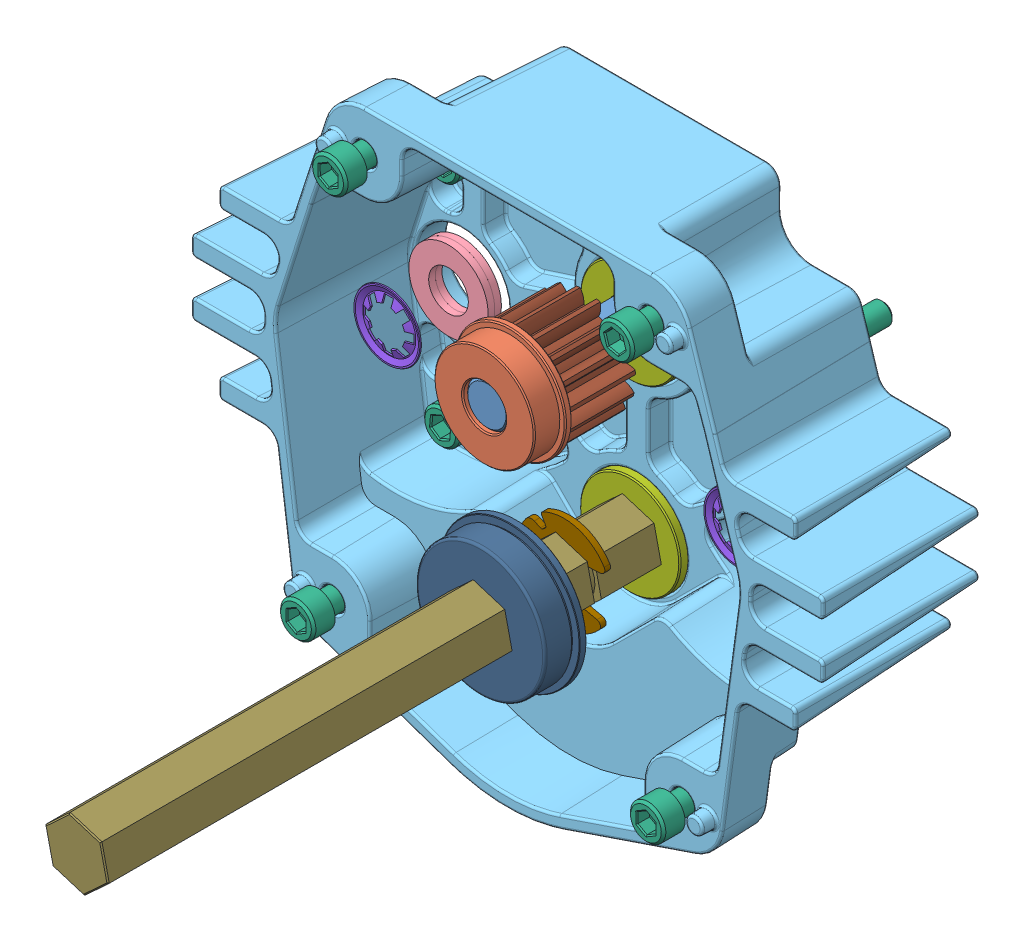
SolidWorks assembly ToughboxMini, configuration Default. Lengths in mm.
Overall size (140.05 118.73 142.29).
27 component instances, 15 part files, 55 mates.
Components (placement in the parent):
- TBMiniSmallHexShaft-1: TBMiniSmallHexShaft [Default] at (-129.7894 33.1737 -52.3959) x (-0.674239 -0.738513 0) z (-0.738513 0.674239 0) size (11 38.23 9.52)
- Bearing_FR6ZZ-1: Bearing_FR6ZZ [Default] at (-96.247 60.278 -52.5991) x (-0.893862 0.448342 0) z (0 0 1) size (24.69 24.69 7.16)
- NylockNut_10-32-1: NylockNut_10-32 [Default] at (-129.8464 -8.0737 -56.3837) x (0.501678 0.865055 0) z (0 0 -1) size (10.18 11.01 7.1)
- NylockNut_10-32-2: NylockNut_10-32 [Default] at (-59.2462 80.7349 -56.3837) x (0.999999 -0.001296 0) z (0 0 -1) size (10.18 11.01 7.1)
- NylockNut_10-32-3: NylockNut_10-32 [Default] at (-122.7461 80.8172 -56.3837) x (0.500567 0.865698 0) z (0 0 -1) size (10.18 11.01 7.1)
- NylockNut_10-32-4: NylockNut_10-32 [Default] at (-52.3764 -8.1741 -56.3837) x (-0.501678 -0.865055 0) z (0 0 -1) size (10.18 11.01 7.1)
- Washer_5-16-1: Washer_5-16 [Default] at (-52.3162 38.3079 -77.7705) x (-0.418041 0.908428 0) z (0 0 -1) size (17.53 17.53 1.47)
- Washer_5-16-2: Washer_5-16 [Default] at (-52.3162 38.3079 -76.2973) x (0.897267 -0.441488 0) z (0 0 -1) size (17.53 17.53 1.47)
- Washer_5-16-3: Washer_5-16 [Default] at (-129.7861 38.4083 -77.7705) x (-0.990116 0.140253 0) z (0 0 1) size (17.53 17.53 1.47)
- Washer_5-16-4: Washer_5-16 [Default] at (-129.7861 38.4083 -79.2437) x (-0.681761 0.731575 0) z (0 0 1) size (17.53 17.53 1.47)
- TBMiniHousing-1: TBMiniHousing [Default] at (-91.0876 10.1882 -86.3557) x (0.999999 -0.001296 0) z (0 0 1) size (139.9 118.55 41.54)
- Screw_SHCS_10-32x0.625-1: Screw_SHCS_10-32x0.625 [Default] at (-52.2832 63.7078 -74.4685) x (-0.564778 -0.825243 0) z (-0.825243 0.564778 0) size (7.82 20.65 7.82)
- Screw_SHCS_10-32x0.625-2: Screw_SHCS_10-32x0.625 [Default] at (-122.7461 80.8172 -42.5915) x (0.507484 -0.861661 0) z (-0.861661 -0.507484 0) size (7.82 20.65 7.82)
- Screw_SHCS_10-32x0.625-3: Screw_SHCS_10-32x0.625 [Default] at (-52.3764 -8.1741 -42.5915) x (0.507484 -0.861661 0) z (-0.861661 -0.507484 0) size (7.82 20.65 7.82)
- Screw_SHCS_10-32x0.625-4: Screw_SHCS_10-32x0.625 [Default] at (-129.8464 -8.0737 -42.5915) x (0.507484 -0.861661 0) z (-0.861661 -0.507484 0) size (7.82 20.65 7.82)
- Screw_SHCS_10-32x0.625-5: Screw_SHCS_10-32x0.625 [Default] at (-59.2462 80.7349 -42.5915) x (0.740711 -0.671824 0) z (-0.671824 -0.740711 0) size (7.82 20.65 7.82)
- Screw_SHCS_10-32x0.625-6: Screw_SHCS_10-32x0.625 [Default] at (-52.3491 12.9079 -74.4685) x (-0.564778 -0.825243 0) z (-0.825243 0.564778 0) size (7.82 20.65 7.82)
- Screw_SHCS_10-32x0.625-7: Screw_SHCS_10-32x0.625 [Default] at (-129.7532 63.8083 -74.4685) x (-0.966277 -0.257503 0) z (-0.257503 0.966277 0) size (7.82 20.65 7.82)
- Screw_SHCS_10-32x0.625-8: Screw_SHCS_10-32x0.625 [Default] at (-129.819 13.0083 -74.4685) x (-0.99652 0.083357 0) z (0.083357 0.99652 0) size (7.82 20.65 7.82)
- Bearing_R6ZZ-3: Bearing_R6ZZ [Default] at (-91.0349 50.9043 -84.8317) x (0.958138 -0.286306 0) z (0 0 1) size (22.23 22.23 7.11)
- Bearing_R6ZZ-4: Bearing_R6ZZ [Default] at (-91.0876 10.1882 -84.8317) x (-0.661529 0.74992 0) z (0 0 1) size (22.23 22.23 7.11)
- RetainingClip-1: RetainingClip [Default] at (-129.7861 38.4083 -63.5973) x (0 0 1) z (-1 0 0) size (1.09 14.83 14.83)
- RetainingClip-2: RetainingClip [Default] at (-52.3162 38.3079 -63.5973) x (0 0 1) z (-1 0 0) size (1.09 14.83 14.83)
- ExternalKlipring-1: ExternalKlipring [Default] at (-91.0876 10.1882 -64.4355) x (0.996411 -0.084651 0) z (0 0 1) size (19.07 20.96 1.27)
- HexBearing_FR8ZZ-1: HexBearing_FR8ZZ [Default] at (-91.0876 10.1882 -44.6717) x (0.73373 0.679441 0) z (0 0 -1) size (31.12 31.12 7.93)
- SmallClusterGear_Hex_16t0.375-1: SmallClusterGear_Hex_16t0.375 [Default] at (-91.0349 50.9043 -67.5597) x (0 0 1) z (0.302452 -0.953165 0) size (15.19 22.57 22.57)
- TBMiniHexOutputShaft-2: TBMiniHexOutputShaft [Default] at (-51.6549 23.9851 -52.3197) x (0.73373 0.679441 0) z (0.679441 -0.73373 0) size (14.66 142.29 12.7)
Mates (geometry in assembly coordinates):
- Concentric2: concentric aligned: circle of NylockNut_10-32-3; circle of TBMiniHousing-1
- Coincident1: coincident anti-aligned: plane of NylockNut_10-32-3 through (-122.7461 80.8172 -56.3837) normal (0 0 1); plane of TBMiniHousing-1 through (-132.6301 80.83 -56.3837) normal (0 0 -1)
- Parallel1: parallel: plane of NylockNut_10-32-3 through (-125.1247 84.9432 -58.368) normal (-0.499433 0.866352 0); line of TBMiniHousing-1 through (-122.993 86.3757 -60.7105) axis (-0.866352 -0.499433 0)
- Concentric3: concentric anti-aligned: circle of NylockNut_10-32-2; circle of TBMiniHousing-1
- Coincident3: coincident anti-aligned: plane of NylockNut_10-32-2 through (-59.2462 80.7349 -56.3837) normal (0 0 1); plane of TBMiniHousing-1 through (-59.2388 86.4499 -56.3837) normal (0 0 -1)
- Parallel2: parallel: plane of NylockNut_10-32-2 through (-54.4837 80.7287 -58.368) normal (0.999999 -0.001296 0); line of TBMiniHousing-1 through (-54.0512 78.1748 -60.9557) axis (0.001296 0.999999 0)
- Concentric4: concentric anti-aligned: circle of NylockNut_10-32-4; circle of TBMiniHousing-1
- Coincident5: coincident anti-aligned: plane of NylockNut_10-32-4 through (-52.3764 -8.1741 -56.3837) normal (0 0 1); plane of TBMiniHousing-1 through (-62.2604 -8.1613 -56.3837) normal (0 0 -1)
- Parallel3: parallel: plane of NylockNut_10-32-4 through (-49.9872 -4.0543 -58.368) normal (0.501678 0.865055 0); line of TBMiniHousing-1 through (-47.5543 -4.9678 -60.9557) axis (-0.865055 0.501678 0)
- Concentric5: concentric aligned: circle of NylockNut_10-32-1; circle of TBMiniHousing-1
- Coincident9: coincident anti-aligned: plane of NylockNut_10-32-1 through (-129.8464 -8.0737 -56.3837) normal (0 0 1); plane of TBMiniHousing-1 through (-139.7304 -8.0609 -56.3837) normal (0 0 -1)
- Parallel4: parallel: plane of NylockNut_10-32-1 through (-132.2356 -12.1935 -58.368) normal (-0.501678 -0.865055 0); line of TBMiniHousing-1 through (-130.235 -13.8511 -60.9557) axis (-0.865055 0.501678 0)
- Concentric6: concentric aligned: cylinder of TBMiniHousing-1 through (-129.7532 63.8083 -50.5417) axis (0 0 1) radius 2.5527; circle of Screw_SHCS_10-32x0.625-7
- Coincident11: coincident anti-aligned: plane of TBMiniHousing-1 through (-59.2462 80.7349 -79.2437) normal (0 0 1); plane of Screw_SHCS_10-32x0.625-7 through (-129.7532 63.8083 -79.2437) normal (0 0 -1)
- Concentric7: concentric anti-aligned: cylinder of TBMiniHousing-1 through (-52.2832 63.7078 -50.5417) axis (0 0 1) radius 2.5527; circle of Screw_SHCS_10-32x0.625-1
- Coincident12: coincident anti-aligned: plane of TBMiniHousing-1 through (-59.2462 80.7349 -79.2437) normal (0 0 1); plane of Screw_SHCS_10-32x0.625-1 through (-52.2832 63.7078 -79.2437) normal (0 0 -1)
- Concentric8: concentric aligned: cylinder of TBMiniHousing-1 through (-52.3491 12.9079 -50.5417) axis (0 0 1) radius 2.5527; cylinder of Screw_SHCS_10-32x0.625-6 through (-52.3491 12.9079 -95.1187) axis (0 0 1) radius 2.3876
- Coincident13: coincident anti-aligned: plane of TBMiniHousing-1 through (-59.2462 80.7349 -79.2437) normal (0 0 1); plane of Screw_SHCS_10-32x0.625-6 through (-52.3491 12.9079 -79.2437) normal (0 0 -1)
- Concentric9: concentric aligned: cylinder of TBMiniHousing-1 through (-129.819 13.0083 -50.5417) axis (0 0 1) radius 2.5527; cylinder of Screw_SHCS_10-32x0.625-8 through (-129.819 13.0083 -95.1187) axis (0 0 1) radius 2.3876
- Coincident14: coincident anti-aligned: plane of TBMiniHousing-1 through (-59.2462 80.7349 -79.2437) normal (0 0 1); plane of Screw_SHCS_10-32x0.625-8 through (-129.819 13.0083 -79.2437) normal (0 0 -1)
- Concentric12: concentric aligned: cylinder of Washer_5-16-3 through (-129.7861 38.4083 -76.2973) axis (0 0 -1) radius 8.763; cylinder of Washer_5-16-4 through (-129.7861 38.4083 -77.7705) axis (0 0 -1) radius 8.763
- Concentric13: concentric anti-aligned: circle of Washer_5-16-4; cylinder of TBMiniHousing-1 through (-129.7861 38.4083 -50.5417) axis (0 0 1) radius 10.414
- Coincident17: coincident anti-aligned: plane of Washer_5-16-4 through (-129.7861 38.4083 -79.2437) normal (0 0 -1); plane of TBMiniHousing-1 through (-59.2462 80.7349 -79.2437) normal (0 0 1)
- Coincident18: coincident anti-aligned: plane of Washer_5-16-3 through (-129.7861 38.4083 -77.7705) normal (0 0 -1); plane of Washer_5-16-4 through (-129.7861 38.4083 -77.7705) normal (0 0 1)
- Coincident21: coincident aligned: circle of Washer_5-16-1; circle of Washer_5-16-2
- Concentric16: concentric aligned: cylinder of Washer_5-16-1 through (-52.3162 38.3079 -79.2437) axis (0 0 1) radius 4.3942; cylinder of TBMiniHousing-1 through (-52.3162 38.3079 -50.5417) axis (0 0 1) radius 10.414
- Coincident22: coincident anti-aligned: plane of Washer_5-16-1 through (-52.3162 38.3079 -79.2437) normal (0 0 -1); plane of TBMiniHousing-1 through (-59.2462 80.7349 -79.2437) normal (0 0 1)
- Concentric27: concentric anti-aligned: cylinder of TBMiniSmallHexShaft-1 through (-91.0349 50.9043 -46.0459) axis (0 0 -1) radius 4.7498; cylinder of Bearing_FR6ZZ-1 through (-91.0349 50.9043 -51.0751) axis (0 0 1) radius 4.7625
- Coincident37: coincident aligned: plane of Screw_SHCS_10-32x0.625-4 through (-129.8464 -8.0737 -47.3667) normal (0 0 -1); plane of Screw_SHCS_10-32x0.625-5 through (-59.2462 80.7349 -47.3667) normal (0 0 -1)
- Coincident39: coincident aligned: plane of Screw_SHCS_10-32x0.625-2 through (-122.7461 80.8172 -47.3667) normal (0 0 -1); plane of Screw_SHCS_10-32x0.625-5 through (-59.2462 80.7349 -47.3667) normal (0 0 -1)
- Coincident40: coincident aligned: plane of Screw_SHCS_10-32x0.625-2 through (-122.7461 80.8172 -47.3667) normal (0 0 -1); plane of Screw_SHCS_10-32x0.625-3 through (-52.3764 -8.1741 -47.3667) normal (0 0 -1)
- Concentric34: concentric anti-aligned: cylinder of TBMiniSmallHexShaft-1 through (-91.0349 50.9043 -84.2729) axis (0 0 1) radius 4.7498; cylinder of Bearing_R6ZZ-3 through (-91.0349 50.9043 -77.7197) axis (0 0 -1) radius 11.1125
- Concentric48: concentric anti-aligned: cylinder of TBMiniHousing-1 through (-91.0876 10.1882 -50.5417) axis (0 0 1) radius 5.08; cylinder of Bearing_R6ZZ-4 through (-91.0876 10.1882 -77.7197) axis (0 0 -1) radius 11.1125
- Coincident60: coincident anti-aligned: plane of TBMiniHousing-1 through (-91.0876 10.1882 -84.8317) normal (0 0 1); plane of Bearing_R6ZZ-4 through (-91.0876 10.1882 -84.8317) normal (0 0 -1)
- Coincident62: coincident aligned: plane of Bearing_FR6ZZ-1 through (-91.0349 50.9043 -51.0751) normal (0 0 1); plane of HexBearing_FR8ZZ-1 through (-80.8374 19.68 -51.0751) normal (0 0 1)
- Coincident63: coincident anti-aligned: plane of TBMiniHousing-1 through (-91.0349 50.9043 -84.8317) normal (0 0 1); plane of Bearing_R6ZZ-3 through (-91.0349 50.9043 -84.8317) normal (0 0 -1)
- Coincident64: coincident anti-aligned: plane of TBMiniSmallHexShaft-1 through (-92.6981 56.146 -77.7197) normal (0 0 -1); plane of Bearing_R6ZZ-3 through (-91.0349 50.9043 -77.7197) normal (0 0 1)
- Coincident69: coincident anti-aligned: plane of TBMiniSmallHexShaft-1 through (-87.327 54.9656 -52.5991) normal (0 0 1); plane of Bearing_FR6ZZ-1 through (-91.0349 50.9043 -52.5991) normal (0 0 -1)
- Concentric52: concentric aligned: cylinder of TBMiniHousing-1 through (-91.0349 50.9043 -84.8317) axis (0 0 -1) radius 11.1061; cylinder of Bearing_R6ZZ-3 through (-91.0349 50.9043 -77.7197) axis (0 0 -1) radius 11.1125
- Distance1: distance = 3.175 mm anti-aligned: plane of TBMiniHousing-1 through (-91.0876 10.1882 -50.5417) normal (0 0 1); plane of Screw_SHCS_10-32x0.625-5 through (-59.2462 80.7349 -47.3667) normal (0 0 -1)
- Concentric53: concentric aligned: cone of TBMiniHousing-1 through (-59.2462 80.7349 -55.8934) axis (0 0 1); cylinder of Screw_SHCS_10-32x0.625-5 through (-59.2462 80.7349 -47.3667) axis (0 0 1) radius 3.9116
- Coincident71: coincident aligned: plane of Screw_SHCS_10-32x0.625-2 through (-122.7461 80.8172 -42.5915) normal (0 0 1); plane of Screw_SHCS_10-32x0.625-5 through (-59.2462 80.7349 -42.5915) normal (0 0 1)
- Concentric54: concentric aligned: cone of TBMiniHousing-1 through (-122.7461 80.8172 -55.8934) axis (0 0 1); cylinder of Screw_SHCS_10-32x0.625-2 through (-122.7461 80.8172 -47.3667) axis (0 0 1) radius 3.9116
- Coincident72: coincident aligned: plane of Screw_SHCS_10-32x0.625-3 through (-52.3764 -8.1741 -42.5915) normal (0 0 1); plane of Screw_SHCS_10-32x0.625-5 through (-59.2462 80.7349 -42.5915) normal (0 0 1)
- Concentric55: concentric aligned: cone of TBMiniHousing-1 through (-52.3764 -8.1741 -55.8934) axis (0 0 1); cylinder of Screw_SHCS_10-32x0.625-3 through (-52.3764 -8.1741 -47.3667) axis (0 0 1) radius 3.9116
- Coincident73: coincident aligned: plane of Screw_SHCS_10-32x0.625-2 through (-122.7461 80.8172 -42.5915) normal (0 0 1); plane of Screw_SHCS_10-32x0.625-4 through (-129.8464 -8.0737 -42.5915) normal (0 0 1)
- Concentric56: concentric aligned: cone of TBMiniHousing-1 through (-129.8464 -8.0737 -55.8934) axis (0 0 1); cylinder of Screw_SHCS_10-32x0.625-4 through (-129.8464 -8.0737 -63.2417) axis (0 0 1) radius 2.3876
- Parallel6: parallel aligned: plane of TBMiniSmallHexShaft-1 through (-96.4059 52.0847 -77.9229) normal (-0.953165 -0.302452 0); plane of SmallClusterGear_Hex_16t0.375-1 through (-85.6638 49.7239 -67.5597) normal (-0.953165 -0.302452 0)
- Concentric59: concentric aligned: cylinder of Bearing_FR6ZZ-1 through (-91.0349 50.9043 -45.4363) axis (0 0 1) radius 11.1125; circle of SmallClusterGear_Hex_16t0.375-1
- Concentric62: concentric anti-aligned: cylinder of Bearing_R6ZZ-4 through (-91.0876 10.1882 -77.7197) axis (0 0 -1) radius 11.1125; cylinder of HexBearing_FR8ZZ-1 through (-91.0876 10.1882 -52.5991) axis (0 0 1) radius 14.2875
- Concentric63: concentric anti-aligned: cylinder of Bearing_R6ZZ-4 through (-91.0876 10.1882 -77.7197) axis (0 0 -1) radius 4.7625; cylinder of TBMiniHexOutputShaft-2 through (-91.0876 10.1882 -84.8317) axis (0 0 1) radius 4.7498
- Coincident82: coincident anti-aligned: plane of Bearing_R6ZZ-4 through (-91.0876 10.1882 -77.7197) normal (0 0 1); plane of TBMiniHexOutputShaft-2 through (-82.4587 0.8698 -77.7197) normal (0 0 -1)
- Coincident83: coincident anti-aligned: plane of HexBearing_FR8ZZ-1 through (-92.7121 17.3383 -52.5991) normal (0.679441 -0.73373 0); plane of TBMiniHexOutputShaft-2 through (-92.7121 17.3383 -77.7197) normal (-0.679441 0.73373 0)
- Concentric64: concentric anti-aligned: cylinder of ExternalKlipring-1 through (-91.0876 10.1882 -63.1655) axis (0 0 -1) radius 5.1562; cylinder of TBMiniHexOutputShaft-2 through (-91.0876 10.1882 -77.7197) axis (0 0 1) radius 5.588
- Coincident85: coincident anti-aligned: plane of ExternalKlipring-1 through (-91.0876 10.1882 -64.4355) normal (0 0 -1); plane of TBMiniHexOutputShaft-2 through (-78.9672 21.4118 -64.4355) normal (0 0 1)
